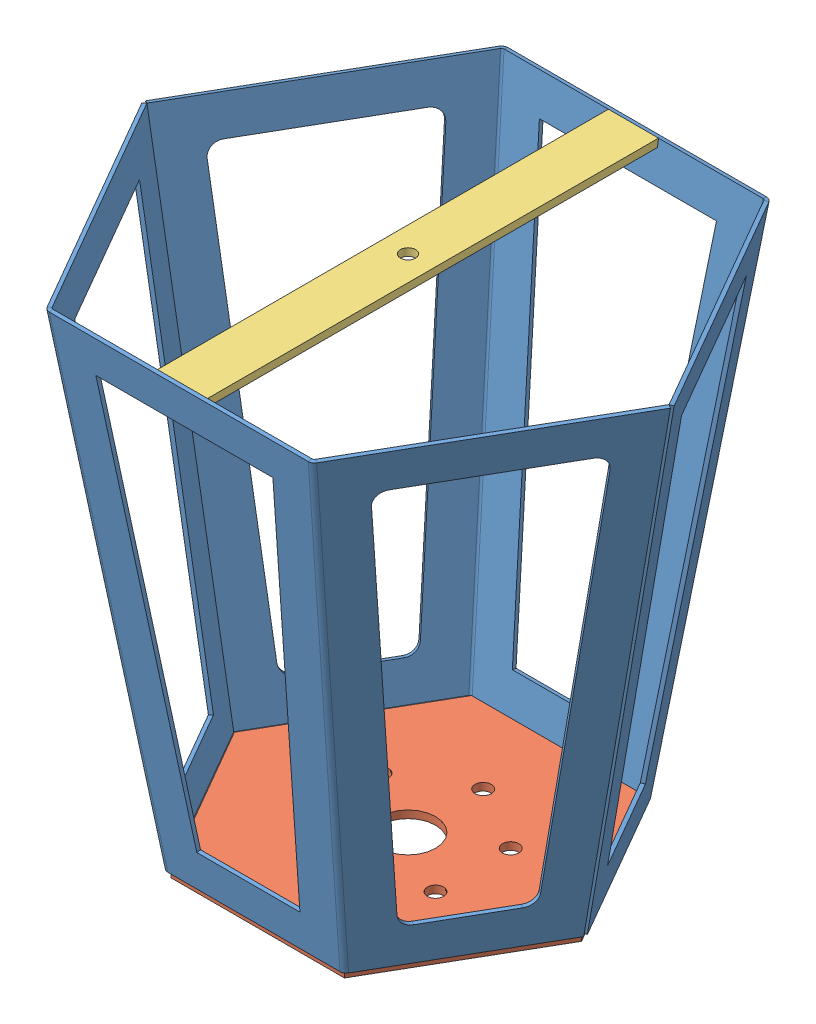
SolidWorks assembly shade-complete, configuration Predeterminado. Lengths in mm.
Overall size (210.99 203 182.97).
4 component instances, 3 part files, 10 mates.
Components (placement in the parent):
- shade1-1: shade1 [Predeterminado] at (0 3 0) size (210.99 200.27 91.49)
- shade1-2: shade1 [Predeterminado] at (0 3 0) x (-1 0 0) z (0 0 -1) size (210.99 200.27 91.49)
- shade-bottom-2: shade-bottom [Predeterminado] at origin size (138.56 3 120)
- Pieza2^shade-complete-1: Pieza2^shade-complete [Predeterminado] at origin size (20 3 180) (virtual)
Mates (geometry in assembly coordinates):
- Coincidente1: coincident aligned: plane of shade1-1 through (0 3 0) normal (0 0 1); plane of assembly through (0 0 0) normal (0 0 1)
- Coincidente2: coincident aligned: plane of shade1-1 through (0 3 0) normal (1 0 0); plane of assembly through (0 0 0) normal (1 0 0)
- Coincidente3: coincident anti-aligned: plane of shade1-2 through (0 3 0) normal (0 0 -1); plane of assembly through (0 0 0) normal (0 0 1)
- Coincidente4: coincident anti-aligned: plane of shade1-2 through (0 3 0) normal (-1 0 0); plane of assembly through (0 0 0) normal (1 0 0)
- Coincidente10: coincident aligned: plane of assembly through (0 3 0) normal (0 1 0); plane of shade1-1 through (0 3 0) normal (0 1 0)
- Coincidente11: coincident aligned: plane of assembly through (0 3 0) normal (0 1 0); plane of shade1-2
- EnPosición1: in place: plane of ? through (0 0 0) normal (0 0 1); moOrthogonalPlaneRef_w of ? through (0 0 0) normal (0 1 0); plane of ? through (0 0 0) normal (1 0 0); unknown of ?
- Coincidente12: coincident aligned: plane of Pieza2^shade-complete-1; plane of assembly
- Coincidente13: coincident aligned: plane of ? through (0 0 0) normal (0 1 0)
- Coincidente14: coincident anti-aligned: plane of ? through (0 0 0) normal (1 0 0)
